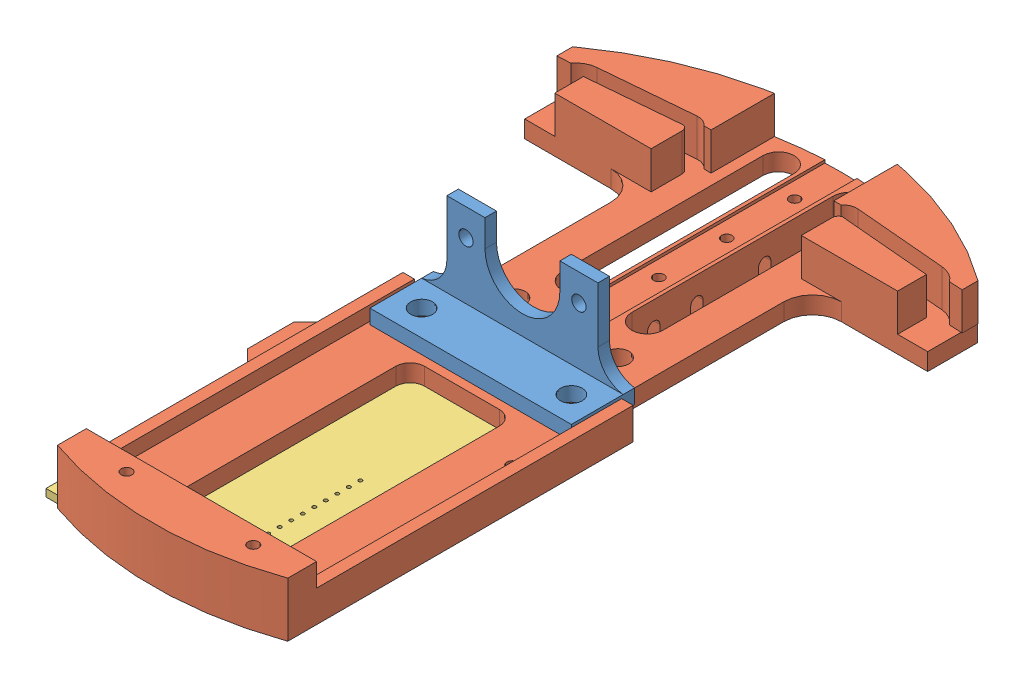
SolidWorks assembly Assem3, configuration Default. Lengths in mm.
Overall size (89.41 37.59 151.89).
3 component instances, 3 part files, 6 mates.
Components (placement in the parent):
- Motor Mount-1: Motor Mount [Default] at (18.8666 37.3977 23.1613) size (44.45 21.72 13.97)
- Baseplate_3-1: Baseplate_3 [Default] at (18.8666 12.6089 31.2893) x (0 0 -1) z (0 1 0) size (151.89 89.41 24.13)
- unoboard blue-1: unoboard blue [Default] at (41.7266 10.9589 34.2819) x (1 0 0) z (0 0 -1) size (53.34 1.65 68.58)
Mates (geometry in assembly coordinates):
- Coincident1: coincident anti-aligned: plane of Motor Mount-1 through (2.2042 16.4189 25.7013) normal (0 -1 0); plane of Baseplate_3-1 through (18.8666 16.4189 31.2893) normal (0 1 0)
- Concentric1: concentric aligned: cylinder of Motor Mount-1 through (35.3766 16.4189 31.4163) axis (0 1 0) radius 2.413; cylinder of Baseplate_3-1 through (35.3766 0.5439 31.4163) axis (0 1 0) radius 2.413
- Concentric2: concentric aligned: cylinder of Motor Mount-1 through (2.3566 16.4189 31.4163) axis (0 1 0) radius 2.413; cylinder of Baseplate_3-1 through (2.3566 0.5439 31.4163) axis (0 1 0) radius 2.413
- Coincident4: coincident: plane of Baseplate_3-1 through (18.8666 12.6089 31.2893) normal (0 -1 0); plane of unoboard blue-1 through (41.7266 12.6089 34.2819) normal (0 1 0)
- Concentric10: concentric: circle of Baseplate_3-1; cylinder of unoboard blue-1 through (6.1666 12.6089 100.3219) axis (0 -1 0) radius 1.5875
- Concentric11: concentric aligned: circle of Baseplate_3-1; circle of unoboard blue-1
